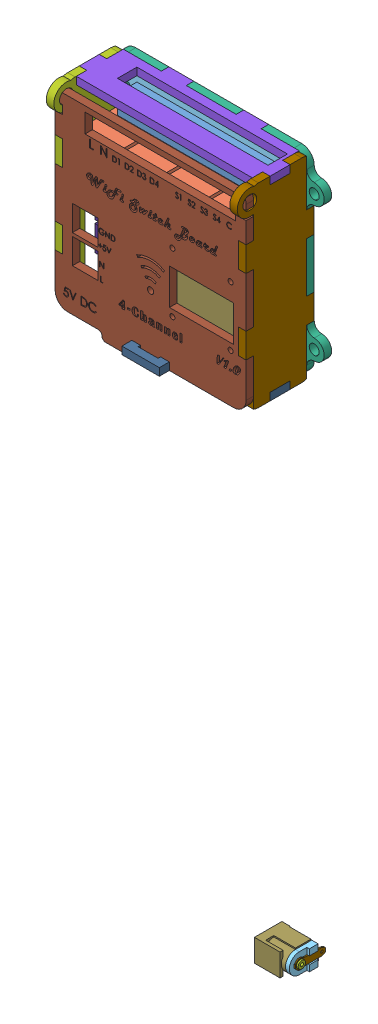
SolidWorks assembly Assem64, configuration Default. Lengths in mm.
Overall size (298.45 81 224.4).
200 component instances, 66 part files, 25 mates.
Components (placement in the parent):
- wifi_switch.STEP-1: wifi_switch.STEP [Default] at (-171.4431 26.4604 -131.7757) size (288.45 72 221.81)
  - 8PIN_TERMINAL.STEP-1: 8PIN_TERMINAL.STEP [Default] at (-41 33.5 0.803) size (60.33 7.62 11.71)
    - Open CASCADE STEP translator 6.8 1.2.1.STEP-1: Open CASCADE STEP translator 6.8 1.2.1.STEP [Default] at origin size (60.33 7.62 11.71)
      - Body_1.STEP-1: Body_1.STEP [Default] at origin size (60.33 7.62 7.8)
      - Pin_1.STEP-1: Pin_1.STEP [Default] x (0 -1 0) z (0 0 1) size (1.42 1.42 8.52)
      - Pin_2.STEP-1: Pin_2.STEP [Default] at (5.0038 5.0038 0) x (0 -1 0) z (0 0 1) size (1.42 1.42 8.52)
      - Pin_3.STEP-1: Pin_3.STEP [Default] at (10.0076 10.0076 0) x (0 -1 0) z (0 0 1) size (1.42 1.42 8.52)
      - Pin_4.STEP-1: Pin_4.STEP [Default] at (15.0114 15.0114 0) x (0 -1 0) z (0 0 1) size (1.42 1.42 8.52)
      - Pin_5.STEP-1: Pin_5.STEP [Default] at (19.9898 19.9898 0) x (0 -1 0) z (0 0 1) size (1.42 1.42 8.52)
      - Pin_6.STEP-1: Pin_6.STEP [Default] at (24.9936 24.9936 0) x (0 -1 0) z (0 0 1) size (1.42 1.42 8.52)
      - Pin_7.STEP-1: Pin_7.STEP [Default] at (29.9974 29.9974 0) x (0 -1 0) z (0 0 1) size (1.42 1.42 8.52)
      - Pin_8.STEP-1: Pin_8.STEP [Default] at (35.0012 35.0012 0) x (0 -1 0) z (0 0 1) size (1.42 1.42 8.52)
      - Pin_9.STEP-1: Pin_9.STEP [Default] at (40.005 40.005 0) x (0 -1 0) z (0 0 1) size (1.42 1.42 8.52)
      - Pin_10.STEP-1: Pin_10.STEP [Default] at (45.0088 45.0088 0) x (0 -1 0) z (0 0 1) size (1.42 1.42 8.52)
      - Pin_11.STEP-1: Pin_11.STEP [Default] at (50.0126 50.0126 0) x (0 -1 0) z (0 0 1) size (1.42 1.42 8.52)
      - Pin_12.STEP-1: Pin_12.STEP [Default] at (54.991 54.991 0) x (0 -1 0) z (0 0 1) size (1.42 1.42 8.52)
  - ESP.STEP-1: ESP.STEP [Default] at (-5.5 -10.5 0.803) size (18.25 24 2.16)
    - Open CASCADE STEP translator 6.8 1.3.1.STEP-1: Open CASCADE STEP translator 6.8 1.3.1.STEP [Default] at origin size (18.25 24 2.16)
      - Body_1-0.STEP-1: Body_1-0.STEP [Default] at origin size (16 24 1.91)
      - Pin_1-1.STEP-1: Pin_1-1.STEP [Default] at origin size (1.12 2.9 1.33)
      - Pin_2-2.STEP-1: Pin_2-2.STEP [Default] at origin size (1.12 2.9 1.33)
      - Pin_3-3.STEP-1: Pin_3-3.STEP [Default] at origin size (1.12 2.9 1.33)
      - Pin_4-4.STEP-1: Pin_4-4.STEP [Default] at origin size (1.12 2.9 1.33)
      - Pin_5-5.STEP-1: Pin_5-5.STEP [Default] at origin size (1.12 2.9 1.33)
      - Pin_6-6.STEP-1: Pin_6-6.STEP [Default] at origin size (1.12 2.9 1.33)
      - Pin_7-7.STEP-1: Pin_7-7.STEP [Default] at origin size (1.12 2.9 1.33)
      - Pin_8-8.STEP-1: Pin_8-8.STEP [Default] at origin size (1.12 2.9 1.33)
      - Pin_9-9.STEP-1: Pin_9-9.STEP [Default] at (0 -28 0) x (-1 0 0) z (0 0 1) size (1.13 2.9 1.33)
      - Pin_10-10.STEP-1: Pin_10-10.STEP [Default] at (0 -24 0) x (-1 0 0) z (0 0 1) size (1.13 2.9 1.33)
      - Pin_11-11.STEP-1: Pin_11-11.STEP [Default] at (0 -20 0) x (-1 0 0) z (0 0 1) size (1.13 2.9 1.33)
      - Pin_12-12.STEP-1: Pin_12-12.STEP [Default] at (0 -16 0) x (-1 0 0) z (0 0 1) size (1.13 2.9 1.33)
      - Pin_13.STEP-1: Pin_13.STEP [Default] at (0 -12 0) x (-1 0 0) z (0 0 1) size (1.13 2.9 1.33)
      - Pin_14.STEP-1: Pin_14.STEP [Default] at (0 -8 0) x (-1 0 0) z (0 0 1) size (1.13 2.9 1.33)
      - Pin_15.STEP-1: Pin_15.STEP [Default] at (0 -4 0) x (-1 0 0) z (0 0 1) size (1.13 2.9 1.33)
      - Pin_16.STEP-1: Pin_16.STEP [Default] x (-1 0 0) z (0 0 1) size (1.13 2.9 1.33)
  - R1_470.STEP-1: R1_470.STEP [Default] at (-36 -18 0.803) x (0 1 0) z (0 0 1) size (4.78 2.7 0.65)
    - Open CASCADE STEP translator 6.8 1.4.1.STEP-1: Open CASCADE STEP translator 6.8 1.4.1.STEP [Default] at origin size (4.78 2.7 0.65)
      - Body_1-13.STEP-1: Body_1-13.STEP [Default] at origin size (4.4 2.68 0.63)
      - Pin_1-14.STEP-1: Pin_1-14.STEP [Default] at (0.374 0 0) x (-1 0 0) z (0 0 1) size (0.45 2.7 0.65)
      - Pin_2-15.STEP-1: Pin_2-15.STEP [Default] at origin size (0.45 2.7 0.65)
  - R3_470.STEP-1: R3_470.STEP [Default] at (2 -9.5 0.803) size (4.78 2.7 0.65)
    - Open CASCADE STEP translator 6.8 1.4.1.STEP-1: Open CASCADE STEP translator 6.8 1.4.1.STEP [Default] at origin size (4.78 2.7 0.65)
      - Body_1-13.STEP-1: Body_1-13.STEP [Default] at origin size (4.4 2.68 0.63)
      - Pin_1-14.STEP-1: Pin_1-14.STEP [Default] at (0.374 0 0) x (-1 0 0) z (0 0 1) size (0.45 2.7 0.65)
      - Pin_2-15.STEP-1: Pin_2-15.STEP [Default] at origin size (0.45 2.7 0.65)
  - R5_470.STEP-1: R5_470.STEP [Default] at (2 -13.5 0.803) size (4.78 2.7 0.65)
    - Open CASCADE STEP translator 6.8 1.4.1.STEP-1: Open CASCADE STEP translator 6.8 1.4.1.STEP [Default] at origin size (4.78 2.7 0.65)
      - Body_1-13.STEP-1: Body_1-13.STEP [Default] at origin size (4.4 2.68 0.63)
      - Pin_1-14.STEP-1: Pin_1-14.STEP [Default] at (0.374 0 0) x (-1 0 0) z (0 0 1) size (0.45 2.7 0.65)
      - Pin_2-15.STEP-1: Pin_2-15.STEP [Default] at origin size (0.45 2.7 0.65)
  - R7_470.STEP-1: R7_470.STEP [Default] at (2 -17.5 0.803) size (4.78 2.7 0.65)
    - Open CASCADE STEP translator 6.8 1.4.1.STEP-1: Open CASCADE STEP translator 6.8 1.4.1.STEP [Default] at origin size (4.78 2.7 0.65)
      - Body_1-13.STEP-1: Body_1-13.STEP [Default] at origin size (4.4 2.68 0.63)
      - Pin_1-14.STEP-1: Pin_1-14.STEP [Default] at (0.374 0 0) x (-1 0 0) z (0 0 1) size (0.45 2.7 0.65)
      - Pin_2-15.STEP-1: Pin_2-15.STEP [Default] at origin size (0.45 2.7 0.65)
  - OP1.STEP-1: OP1.STEP [Default] at (-35.5 -11 0.803) size (5.08 7.92 7.75)
    - Open CASCADE STEP translator 6.8 1.8.1.STEP-1: Open CASCADE STEP translator 6.8 1.8.1.STEP [Default] at origin size (5.08 7.92 7.75)
      - Body_1-16.STEP-1: Body_1-16.STEP [Default] at (1.3 3.7 0) x (0 1 0) z (1 0 0) size (7.92 7.75 5.08)
  - OP2.STEP-1: OP2.STEP [Default] at (12.5 -8.5 0.803) size (5.08 7.92 7.75)
    - Open CASCADE STEP translator 6.8 1.9.1.STEP-1: Open CASCADE STEP translator 6.8 1.9.1.STEP [Default] at origin size (5.08 7.92 7.75)
      - Body_1-16.STEP-1: Body_1-16.STEP [Default] at (1.3 3.7 0) x (0 1 0) z (1 0 0) size (7.92 7.75 5.08)
  - OP3.STEP-1: OP3.STEP [Default] at (12.5 -18 0.803) size (5.08 7.92 7.75)
    - Open CASCADE STEP translator 6.8 1.10.1.STEP-1: Open CASCADE STEP translator 6.8 1.10.1.STEP [Default] at origin size (5.08 7.92 7.75)
      - Body_1-16.STEP-1: Body_1-16.STEP [Default] at (1.3 3.7 0) x (0 1 0) z (1 0 0) size (7.92 7.75 5.08)
  - OP4.STEP-1: OP4.STEP [Default] at (12.5 -28 0.803) size (5.08 7.92 7.75)
    - Open CASCADE STEP translator 6.8 1.11.1.STEP-1: Open CASCADE STEP translator 6.8 1.11.1.STEP [Default] at origin size (5.08 7.92 7.75)
      - Body_1-16.STEP-1: Body_1-16.STEP [Default] at (1.3 3.7 0) x (0 1 0) z (1 0 0) size (7.92 7.75 5.08)
  - SMPS_5V_GND.STEP-1: SMPS_5V_GND.STEP [Default] at (-43.5 -4.5 0.803) x (0 1 0) z (0 0 1) size (10.16 10.16 15.71)
    - Open CASCADE STEP translator 6.8 1.12.1.STEP-1: Open CASCADE STEP translator 6.8 1.12.1.STEP [Default] at origin size (10.16 10.16 15.71)
      - Body_1-17.STEP-1: Body_1-17.STEP [Default] at origin size (10.16 10.16 11.8)
      - Pin_1-18.STEP-1: Pin_1-18.STEP [Default] x (0 -1 0) z (0 0 1) size (1.42 1.42 10.52)
      - Pin_2-19.STEP-1: Pin_2-19.STEP [Default] at (5.08 5.08 0) x (0 -1 0) z (0 0 1) size (1.42 1.42 10.52)
  - SMPS_L_N.STEP-1: SMPS_L_N.STEP [Default] at (-43.5 -16 0.803) x (0 1 0) z (0 0 1) size (10.16 10.16 15.71)
    - Open CASCADE STEP translator 6.8 1.12.1.STEP-1: Open CASCADE STEP translator 6.8 1.12.1.STEP [Default] at origin size (10.16 10.16 15.71)
      - Body_1-17.STEP-1: Body_1-17.STEP [Default] at origin size (10.16 10.16 11.8)
      - Pin_1-18.STEP-1: Pin_1-18.STEP [Default] x (0 -1 0) z (0 0 1) size (1.42 1.42 10.52)
      - Pin_2-19.STEP-1: Pin_2-19.STEP [Default] at (5.08 5.08 0) x (0 -1 0) z (0 0 1) size (1.42 1.42 10.52)
  - RL4.STEP-1: RL4.STEP [Default] at (-31 10 0.803) x (0 1 0) z (0 0 1) size (19.8 15.8 19.1)
    - Open CASCADE STEP translator 6.8 1.14.1.STEP-1: Open CASCADE STEP translator 6.8 1.14.1.STEP [Default] at origin size (19.8 15.8 19.1)
      - Body_1-20.STEP-1: Body_1-20.STEP [Default] at (6.5 -6 0) x (1 0 0) z (0 -1 0) size (19.8 19.1 15.8)
        - 1.STEP-1: 1.STEP [Default] at origin size (19.8 19.1 15.8)
        - 2.STEP-1: 2.STEP [Default] at origin size (1 4 0.4)
  - RL1.STEP-1: RL1.STEP [Default] at (-48 10 0.803) x (0 1 0) z (0 0 1) size (19.8 15.8 19.1)
    - Open CASCADE STEP translator 6.8 1.15.1.STEP-1: Open CASCADE STEP translator 6.8 1.15.1.STEP [Default] at origin size (19.8 15.8 19.1)
      - Body_1-1.STEP-1: Body_1-1.STEP [Default] at (6.5 -6 0) x (1 0 0) z (0 -1 0) size (19.8 19.1 15.8)
        - 1.STEP-1: 1.STEP [Default] at origin size (19.8 19.1 15.8)
        - 2.STEP-1: 2.STEP [Default] at origin size (1 4 0.4)
  - RL2.STEP-1: RL2.STEP [Default] at (-14 10 0.803) x (0 1 0) z (0 0 1) size (19.8 15.8 19.1)
    - Open CASCADE STEP translator 6.8 1.16.1.STEP-1: Open CASCADE STEP translator 6.8 1.16.1.STEP [Default] at origin size (19.8 15.8 19.1)
      - Body_1-2.STEP-1: Body_1-2.STEP [Default] at (6.5 -6 0) x (1 0 0) z (0 -1 0) size (19.8 19.1 15.8)
        - 1.STEP-1: 1.STEP [Default] at origin size (19.8 19.1 15.8)
        - 2.STEP-1: 2.STEP [Default] at origin size (1 4 0.4)
  - RL3.STEP-1: RL3.STEP [Default] at (3 10 0.803) x (0 1 0) z (0 0 1) size (19.8 15.8 19.1)
    - Open CASCADE STEP translator 6.8 1.17.1.STEP-1: Open CASCADE STEP translator 6.8 1.17.1.STEP [Default] at origin size (19.8 15.8 19.1)
      - Body_1-3.STEP-1: Body_1-3.STEP [Default] at (6.5 -6 0) x (1 0 0) z (0 -1 0) size (19.8 19.1 15.8)
        - 1.STEP-1: 1.STEP [Default] at origin size (19.8 19.1 15.8)
        - 2.STEP-1: 2.STEP [Default] at origin size (1 4 0.4)
  - DISPLAY_CONNECTOR.STEP-1: DISPLAY_CONNECTOR.STEP [Default] at (0 0 0.803) size (10.16 2.54 7.37)
    - Open CASCADE STEP translator 6.8 1.18.1.STEP-1: Open CASCADE STEP translator 6.8 1.18.1.STEP [Default] at origin size (10.16 2.54 7.37)
      - Body_1-21.STEP-1: Body_1-21.STEP [Default] at (3.8 0 0) x (1 0 0) z (0 -1 0) size (10.16 7.37 2.54)
  - DC_JACK.STEP-1: DC_JACK.STEP [Default] at (-42 -24.5 0.803) x (0 -1 0) z (0 0 1) size (9.5 14.51 14.4)
    - Open CASCADE STEP translator 6.8 1.19.1.STEP-1: Open CASCADE STEP translator 6.8 1.19.1.STEP [Default] at origin size (9.5 14.51 14.4)
      - Body_1-4.STEP-1: Body_1-4.STEP [Default] at (-1.97 277.95 212.6) x (-1 0 0) z (0 1 0) size (9.5 14.4 14.51)
        - =_[0_1_1_3].STEP-1: =_[0_1_1_3].STEP [Default] at origin size (8 10.5 2.55)
        - =_[0_1_1_4].STEP-1: =_[0_1_1_4].STEP [Default] at origin size (1.93 1.93 11.95)
        - =_[0_1_1_5].STEP-1: =_[0_1_1_5].STEP [Default] at origin size (3.3 3.3 1)
        - =_[0_1_1_6].STEP-1: =_[0_1_1_6].STEP [Default] at origin size (1.5 7.4 7.5)
        - =_[0_1_1_7].STEP-1: =_[0_1_1_7].STEP [Default] at origin size (4 12 0.5)
        - =_[0_1_1_8].STEP-1: =_[0_1_1_8].STEP [Default] at origin size (3.5 3.5 0.2)
        - =_[0_1_1_9].STEP-1: =_[0_1_1_9].STEP [Default] at origin size (2.5 3.7 0.2)
        - =_[0_1_1_10].STEP-1: =_[0_1_1_10].STEP [Default] at origin size (9 11 11.96)
  - RX.STEP-1: RX.STEP [Default] at (-3.5 -5 0.803) size (5.08 2.54 7.37)
    - Open CASCADE STEP translator 6.8 1.20.1.STEP-1: Open CASCADE STEP translator 6.8 1.20.1.STEP [Default] at origin size (5.08 2.54 7.37)
      - Body_1-22.STEP-1: Body_1-22.STEP [Default] at (1.3 0 0) x (1 0 0) z (0 -1 0) size (5.08 7.37 2.54)
  - Q1.STEP-1: Q1.STEP [Default] at (-34 1 0.803) size (4.8 20.44 3.83)
    - Open CASCADE STEP translator 6.8 1.21.1.STEP-1: Open CASCADE STEP translator 6.8 1.21.1.STEP [Default] at origin size (4.8 20.44 3.83)
      - Body_1-5.STEP-1: Body_1-5.STEP [Default] at origin size (4.8 20.44 3.83)
        - =_[0_1_1_3]-23.STEP-1: =_[0_1_1_3]-23.STEP [Default] at origin size (0.48 15.53 0.43)
        - =_[0_1_1_4]-24.STEP-1: =_[0_1_1_4]-24.STEP [Default] at origin size (0.49 15.53 0.43)
        - =_[0_1_1_5]-25.STEP-1: =_[0_1_1_5]-25.STEP [Default] at origin size (0.48 15.53 0.43)
        - =_[0_1_1_6]-26.STEP-1: =_[0_1_1_6]-26.STEP [Default] at origin size (4.8 4.95 3.83)
        - =_[0_1_1_7]-27.STEP-1: =_[0_1_1_7]-27.STEP [Default] at origin size (0.7 0.7 0.05)
  - Q2.STEP-1: Q2.STEP [Default] at (-10 1 0.803) size (4.8 20.44 3.83)
    - Open CASCADE STEP translator 6.8 1.22.1.STEP-1: Open CASCADE STEP translator 6.8 1.22.1.STEP [Default] at origin size (4.8 20.44 3.83)
      - Body_1-5.STEP-1: Body_1-5.STEP [Default] at origin size (4.8 20.44 3.83)
        - =_[0_1_1_3]-23.STEP-1: =_[0_1_1_3]-23.STEP [Default] at origin size (0.48 15.53 0.43)
        - =_[0_1_1_4]-24.STEP-1: =_[0_1_1_4]-24.STEP [Default] at origin size (0.49 15.53 0.43)
        - =_[0_1_1_5]-25.STEP-1: =_[0_1_1_5]-25.STEP [Default] at origin size (0.48 15.53 0.43)
        - =_[0_1_1_6]-26.STEP-1: =_[0_1_1_6]-26.STEP [Default] at origin size (4.8 4.95 3.83)
        - =_[0_1_1_7]-27.STEP-1: =_[0_1_1_7]-27.STEP [Default] at origin size (0.7 0.7 0.05)
  - Q3.STEP-1: Q3.STEP [Default] at (-16.5 1 0.803) size (4.8 20.44 3.83)
    - Open CASCADE STEP translator 6.8 1.23.1.STEP-1: Open CASCADE STEP translator 6.8 1.23.1.STEP [Default] at origin size (4.8 20.44 3.83)
      - Body_1-5.STEP-1: Body_1-5.STEP [Default] at origin size (4.8 20.44 3.83)
        - =_[0_1_1_3]-23.STEP-1: =_[0_1_1_3]-23.STEP [Default] at origin size (0.48 15.53 0.43)
        - =_[0_1_1_4]-24.STEP-1: =_[0_1_1_4]-24.STEP [Default] at origin size (0.49 15.53 0.43)
        - =_[0_1_1_5]-25.STEP-1: =_[0_1_1_5]-25.STEP [Default] at origin size (0.48 15.53 0.43)
        - =_[0_1_1_6]-26.STEP-1: =_[0_1_1_6]-26.STEP [Default] at origin size (4.8 4.95 3.83)
        - =_[0_1_1_7]-27.STEP-1: =_[0_1_1_7]-27.STEP [Default] at origin size (0.7 0.7 0.05)
  - Q4.STEP-1: Q4.STEP [Default] at (-22.5 1 0.803) size (4.8 20.44 3.83)
    - Open CASCADE STEP translator 6.8 1.24.1.STEP-1: Open CASCADE STEP translator 6.8 1.24.1.STEP [Default] at origin size (4.8 20.44 3.83)
      - Body_1-5.STEP-1: Body_1-5.STEP [Default] at origin size (4.8 20.44 3.83)
        - =_[0_1_1_3]-23.STEP-1: =_[0_1_1_3]-23.STEP [Default] at origin size (0.48 15.53 0.43)
        - =_[0_1_1_4]-24.STEP-1: =_[0_1_1_4]-24.STEP [Default] at origin size (0.49 15.53 0.43)
        - =_[0_1_1_5]-25.STEP-1: =_[0_1_1_5]-25.STEP [Default] at origin size (0.48 15.53 0.43)
        - =_[0_1_1_6]-26.STEP-1: =_[0_1_1_6]-26.STEP [Default] at origin size (4.8 4.95 3.83)
        - =_[0_1_1_7]-27.STEP-1: =_[0_1_1_7]-27.STEP [Default] at origin size (0.7 0.7 0.05)
  - R2_120.STEP-1: R2_120.STEP [Default] at (-32 -18 0.803) x (0 1 0) z (0 0 1) size (4.78 2.7 0.65)
    - Open CASCADE STEP translator 6.8 1.4.1.STEP-1: Open CASCADE STEP translator 6.8 1.4.1.STEP [Default] at origin size (4.78 2.7 0.65)
      - Body_1-13.STEP-1: Body_1-13.STEP [Default] at origin size (4.4 2.68 0.63)
      - Pin_1-14.STEP-1: Pin_1-14.STEP [Default] at (0.374 0 0) x (-1 0 0) z (0 0 1) size (0.45 2.7 0.65)
      - Pin_2-15.STEP-1: Pin_2-15.STEP [Default] at origin size (0.45 2.7 0.65)
  - R4_120.STEP-1: R4_120.STEP [Default] at (2 -21.5 0.803) size (4.78 2.7 0.65)
    - Open CASCADE STEP translator 6.8 1.4.1.STEP-1: Open CASCADE STEP translator 6.8 1.4.1.STEP [Default] at origin size (4.78 2.7 0.65)
      - Body_1-13.STEP-1: Body_1-13.STEP [Default] at origin size (4.4 2.68 0.63)
      - Pin_1-14.STEP-1: Pin_1-14.STEP [Default] at (0.374 0 0) x (-1 0 0) z (0 0 1) size (0.45 2.7 0.65)
      - Pin_2-15.STEP-1: Pin_2-15.STEP [Default] at origin size (0.45 2.7 0.65)
  - R6_120.STEP-1: R6_120.STEP [Default] at (2 -25.5 0.803) size (4.78 2.7 0.65)
    - Open CASCADE STEP translator 6.8 1.4.1.STEP-1: Open CASCADE STEP translator 6.8 1.4.1.STEP [Default] at origin size (4.78 2.7 0.65)
      - Body_1-13.STEP-1: Body_1-13.STEP [Default] at origin size (4.4 2.68 0.63)
      - Pin_1-14.STEP-1: Pin_1-14.STEP [Default] at (0.374 0 0) x (-1 0 0) z (0 0 1) size (0.45 2.7 0.65)
      - Pin_2-15.STEP-1: Pin_2-15.STEP [Default] at origin size (0.45 2.7 0.65)
  - R8_120.STEP-1: R8_120.STEP [Default] at (2 -29.5 0.803) size (4.78 2.7 0.65)
    - Open CASCADE STEP translator 6.8 1.4.1.STEP-1: Open CASCADE STEP translator 6.8 1.4.1.STEP [Default] at origin size (4.78 2.7 0.65)
      - Body_1-13.STEP-1: Body_1-13.STEP [Default] at origin size (4.4 2.68 0.63)
      - Pin_1-14.STEP-1: Pin_1-14.STEP [Default] at (0.374 0 0) x (-1 0 0) z (0 0 1) size (0.45 2.7 0.65)
      - Pin_2-15.STEP-1: Pin_2-15.STEP [Default] at origin size (0.45 2.7 0.65)
  - PN1.STEP-1: PN1.STEP [Default] at (-28.5 1 0.803) size (3.05 1.5 2.16)
    - Open CASCADE STEP translator 6.8 1.29.1.STEP-1: Open CASCADE STEP translator 6.8 1.29.1.STEP [Default] at origin size (3.05 1.5 2.16)
      - Body_1-28.STEP-1: Body_1-28.STEP [Default] at origin size (0.4 0.8 1.91)
      - Pin_1-29.STEP-1: Pin_1-29.STEP [Default] at origin size (1.32 1.5 1.33)
      - Pin_2-30.STEP-1: Pin_2-30.STEP [Default] at (2.8 0 0) x (-1 0 0) z (0 0 1) size (1.32 1.5 1.33)
  - PN2.STEP-1: PN2.STEP [Default] at (-27.5 -3 0.803) size (3.05 1.5 2.16)
    - Open CASCADE STEP translator 6.8 1.29.1.STEP-1: Open CASCADE STEP translator 6.8 1.29.1.STEP [Default] at origin size (3.05 1.5 2.16)
      - Body_1-28.STEP-1: Body_1-28.STEP [Default] at origin size (0.4 0.8 1.91)
      - Pin_1-29.STEP-1: Pin_1-29.STEP [Default] at origin size (1.32 1.5 1.33)
      - Pin_2-30.STEP-1: Pin_2-30.STEP [Default] at (2.8 0 0) x (-1 0 0) z (0 0 1) size (1.32 1.5 1.33)
  - PN3.STEP-1: PN3.STEP [Default] at (-27.5 -7.5 0.803) size (3.05 1.5 2.16)
    - Open CASCADE STEP translator 6.8 1.29.1.STEP-1: Open CASCADE STEP translator 6.8 1.29.1.STEP [Default] at origin size (3.05 1.5 2.16)
      - Body_1-28.STEP-1: Body_1-28.STEP [Default] at origin size (0.4 0.8 1.91)
      - Pin_1-29.STEP-1: Pin_1-29.STEP [Default] at origin size (1.32 1.5 1.33)
      - Pin_2-30.STEP-1: Pin_2-30.STEP [Default] at (2.8 0 0) x (-1 0 0) z (0 0 1) size (1.32 1.5 1.33)
  - PN4.STEP-1: PN4.STEP [Default] at (5.5 -4 0.803) size (3.05 1.5 2.16)
    - Open CASCADE STEP translator 6.8 1.29.1.STEP-1: Open CASCADE STEP translator 6.8 1.29.1.STEP [Default] at origin size (3.05 1.5 2.16)
      - Body_1-28.STEP-1: Body_1-28.STEP [Default] at origin size (0.4 0.8 1.91)
      - Pin_1-29.STEP-1: Pin_1-29.STEP [Default] at origin size (1.32 1.5 1.33)
      - Pin_2-30.STEP-1: Pin_2-30.STEP [Default] at (2.8 0 0) x (-1 0 0) z (0 0 1) size (1.32 1.5 1.33)
  - PROG.STEP-1: PROG.STEP [Default] at (-28.103 -24 0.803) x (0 1 0) z (0 0 1) size (15.24 2.54 7.37)
    - Open CASCADE STEP translator 6.8 1.33.1.STEP-1: Open CASCADE STEP translator 6.8 1.33.1.STEP [Default] at origin size (15.24 2.54 7.37)
      - Body_1-31.STEP-1: Body_1-31.STEP [Default] at (6.5 0 0) x (1 0 0) z (0 -1 0) size (15.24 7.37 2.54)
  - RESET.STEP-1: RESET.STEP [Default] at (-0.5 -26.5 0.803) x (0 1 0) z (0 0 1) size (5.08 2.54 7.37)
    - Open CASCADE STEP translator 6.8 1.34.1.STEP-1: Open CASCADE STEP translator 6.8 1.34.1.STEP [Default] at origin size (5.08 2.54 7.37)
      - Body_1-22.STEP-1: Body_1-22.STEP [Default] at (1.3 0 0) x (1 0 0) z (0 -1 0) size (5.08 7.37 2.54)
  - Layer_1.STEP-1: Layer_1.STEP [Default] at origin size (70.5 72 1.61)
- bottom_plate-1: bottom_plate [Default] at (-179.4431 42.9604 -134.2727) x (0 -1 0) z (0 0 -1) size (78 90.5 3)
- side_plate-1: side_plate [Default] at (-223.9431 42.9604 -134.2727) x (0 -1 0) z (-1 0 0) size (78 30.87 3)
- terminal_block_plate-1: terminal_block_plate [Default] at (-179.4431 65.9604 -134.2727) x (0 0 -1) z (0 1 0) size (21.81 76.5 3)
- side_plate2-1: side_plate2 [Default] at (-150.4431 42.9604 -134.2727) x (0 -1 0) z (-1 0 0) size (78 30.87 3)
- back_plate-1: back_plate [Default] at (-179.4431 -6.0396 -112.9609) x (0 0 1) z (0 -1 0) size (31.31 73.5 3)
- top_plate-1: top_plate [Default] at (-179.4431 16.9604 -112.9609) x (0 1 0) z (0 0 1) size (78 76.5 3)
- OLED TFT 0.96 inch 64x128 monochrome-1: OLED TFT 0.96 inch 64x128 monochrome [Default] at (-168.2931 8.2604 -115.5609) x (-1 0 0) z (0 1 0) size (27.3 12.3 27.8)
Mates (geometry in assembly coordinates):
- InPlace1: in place: plane of ? through (-94.1181 6.3884 -114.7356) normal (0 0 -1); plane of ? through (0 0 -114.7356) normal (0 0 -1); moOrthogonalPlaneRef_w of ? through (-94.1181 6.3884 -114.7356) normal (0 0 -1); plane of ? through (0 0 -114.7356) normal (0 1 0); plane of ? through (-94.1181 6.3884 -114.7356) normal (0 0 -1); plane of ? through (0 0 -114.7356) normal (-1 0 0); plane of ? through (-179.4431 34.4604 -134.2727) normal (0 0 -1); unknown of bottom_plate-1
- Coincident1: coincident aligned: plane of wifi_switch.STEP-1/RL2.STEP-1/Open CASCADE STEP translator 6.8 1.16.1.STEP-1/Body_1-2.STEP-1/1.STEP-1; plane of bottom_plate-1
- Coincident2: coincident aligned: moOrthogonalPlaneRef_w of wifi_switch.STEP-1/RL2.STEP-1/Open CASCADE STEP translator 6.8 1.16.1.STEP-1/Body_1-2.STEP-1/1.STEP-1 through (-179.4431 42.9604 -134.2727) normal (-1 0 0); plane of bottom_plate-1 through (-179.4431 42.9604 -134.2727) normal (-1 0 0)
- Coincident3: coincident anti-aligned: moOrthogonalPlaneRef_w of wifi_switch.STEP-1/RL2.STEP-1/Open CASCADE STEP translator 6.8 1.16.1.STEP-1/Body_1-2.STEP-1/1.STEP-1 through (-179.4431 42.9604 -134.2727) normal (0 1 0); plane of bottom_plate-1 through (-179.4431 42.9604 -134.2727) normal (0 -1 0)
- InPlace2: in place: plane of ? through (-139.6181 21.8884 -117.7356) normal (-1 0 0); plane of ? through (-139.6181 0 0) normal (-1 0 0); plane of ? through (-139.6181 21.8884 -117.7356) normal (-1 0 0); plane of ? through (-139.6181 0 0) normal (0 1 0); plane of ? through (-139.6181 21.8884 -117.7356) normal (-1 0 0); plane of ? through (-139.6181 0 0) normal (0 0 1); plane of bottom_plate-1 through (-223.9431 49.9604 -137.2727) normal (-1 0 0); unknown of side_plate-1
- Coincident4: coincident aligned: plane of bottom_plate-1; plane of side_plate-1
- Coincident5: coincident aligned: moOrthogonalPlaneRef_w of bottom_plate-1 through (-223.9431 42.9604 -134.2727) normal (0 0 1); plane of side_plate-1 through (-223.9431 42.9604 -134.2727) normal (0 0 1)
- Coincident6: coincident anti-aligned: moOrthogonalPlaneRef_w of bottom_plate-1 through (-223.9431 42.9604 -134.2727) normal (0 1 0); plane of side_plate-1 through (-223.9431 42.9604 -134.2727) normal (0 -1 0)
- InPlace3: in place: plane of ? through (-93.3681 37.8884 -117.7356) normal (0 1 0); plane of ? through (0 37.8884 0) normal (0 1 0); plane of ? through (-93.3681 37.8884 -117.7356) normal (0 1 0); plane of ? through (0 37.8884 0) normal (0 0 -1); plane of ? through (-93.3681 37.8884 -117.7356) normal (0 1 0); plane of ? through (0 37.8884 0) normal (1 0 0); plane of bottom_plate-1 through (-178.6931 65.9604 -137.2727) normal (0 1 0); unknown of terminal_block_plate-1
- Coincident5: coincident aligned: plane of bottom_plate-1; plane of terminal_block_plate-1
- Coincident6: coincident aligned: moOrthogonalPlaneRef_w of bottom_plate-1 through (-179.4431 65.9604 -134.2727) normal (-1 0 0); plane of terminal_block_plate-1 through (-179.4431 65.9604 -134.2727) normal (-1 0 0)
- Coincident7: coincident anti-aligned: moOrthogonalPlaneRef_w of bottom_plate-1 through (-179.4431 65.9604 -134.2727) normal (0 0 1); plane of terminal_block_plate-1 through (-179.4431 65.9604 -134.2727) normal (0 0 -1)
- Coincident1: coincident anti-aligned: plane of bottom_plate-1 through (-153.4431 9.9604 -137.2727) normal (1 0 0); plane of side_plate2-1 through (-153.4431 -4.0396 -114.9609) normal (-1 0 0)
- Coincident2: coincident aligned: plane of bottom_plate-1 through (-221.9431 63.9604 -137.2727) normal (0 0 -1); plane of side_plate2-1 through (-153.4431 49.9604 -137.2727) normal (0 0 -1)
- Coincident3: coincident anti-aligned: plane of bottom_plate-1 through (-150.4431 49.9604 -137.2727) normal (0 -1 0); plane of side_plate2-1 through (-153.4431 49.9604 -134.2727) normal (0 1 0)
- Coincident4: coincident aligned: plane of bottom_plate-1 through (-221.9431 63.9604 -137.2727) normal (0 0 -1); plane of back_plate-1 through (-168.6931 -9.0396 -137.2727) normal (0 0 -1)
- Coincident5: coincident aligned: plane of bottom_plate-1 through (-155.4431 -9.0396 -137.2727) normal (0 -1 0); plane of back_plate-1 through (-179.4431 -9.0396 -112.9609) normal (0 -1 0)
- Coincident6: coincident anti-aligned: plane of side_plate2-1 through (-153.4431 -4.0396 -114.9609) normal (-1 0 0); plane of back_plate-1 through (-153.4431 -9.0396 -112.9609) normal (1 0 0)
- Coincident10: coincident aligned: plane of back_plate-1 through (-179.4431 -9.0396 -112.9609) normal (0 -1 0); plane of top_plate-1 through (-221.9431 -9.0396 -109.9609) normal (0 -1 0)
- Coincident11: coincident aligned: plane of side_plate2-1 through (-150.4431 -4.0396 -114.9609) normal (1 0 0); plane of top_plate-1 through (-150.4431 -4.0396 -109.9609) normal (1 0 0)
- Coincident12: coincident aligned: plane of side_plate2-1 through (-153.4431 19.9604 -109.9609) normal (0 0 1); plane of top_plate-1 through (-221.9431 -4.0396 -109.9609) normal (0 0 1)
- Parallel1: parallel aligned: plane of side_plate2-1 through (-150.4431 -4.0396 -114.9609) normal (1 0 0); plane of OLED TFT 0.96 inch 64x128 monochrome-1 through (-154.6431 36.0604 -114.3609) normal (1 0 0)
- Distance1: distance = 4.2 mm aligned: plane of OLED TFT 0.96 inch 64x128 monochrome-1 through (-154.6431 36.0604 -114.3609) normal (1 0 0); plane of side_plate2-1 through (-150.4431 -4.0396 -114.9609) normal (1 0 0)
- Distance2: distance = 17.3 mm aligned: plane of OLED TFT 0.96 inch 64x128 monochrome-1 through (-154.6431 8.2604 -114.3609) normal (0 -1 0); plane of top_plate-1 through (-221.9431 -9.0396 -109.9609) normal (0 -1 0)
- Coincident16: coincident anti-aligned: plane of top_plate-1 through (-221.9431 -4.0396 -112.9609) normal (0 0 -1); plane of OLED TFT 0.96 inch 64x128 monochrome-1 through (-168.2931 8.2604 -112.9609) normal (0 0 1)
